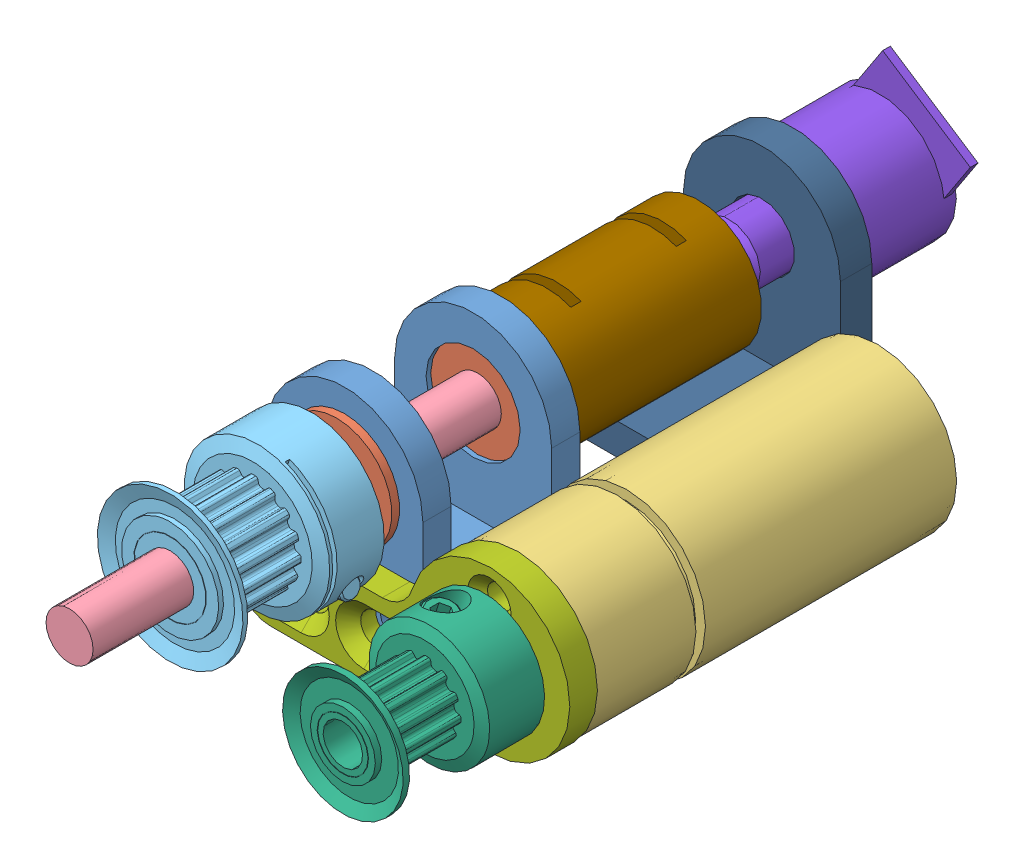
SolidWorks assembly head-pin-joint, configuration Default. Lengths in mm.
Overall size (34.59 24.97 83.16).
12 component instances, 11 part files, 25 mates.
Components (placement in the parent):
- n05-headyoke-1: n05-headyoke [Default] at origin size (15.88 21.91 15.88)
- p1875bearing-57155K319-MCM-1: p1875bearing-57155K319-MCM [Default] at (0 13.97 5.5499) x (0 0 -1) z (0 -1 0) size (3.17 11.18 11.18)
- p1875bearing-57155K319-MCM-2: p1875bearing-57155K319-MCM [Default] at (0 13.97 -5.5499) x (0 0 1) z (0 -1 0) size (3.17 11.18 11.18)
- MAXON-AMAX16-110049-110323-1: MAXON-AMAX16-110049-110323 [Default] at (17.4625 8.128 -28.5125) x (0 0 -1) z (1 0 0) size (48.2 16 16)
- n06-p1875shaft-1: n06-p1875shaft [Default] at (0 13.97 -15.0749) size (4.76 4.76 50.8)
- a_6d16-016df2506-p1875bore-16teeth-1: a_6d16-016df2506-p1875bore-16teeth [Default] at (0 13.97 17.218) x (0.167713 -0.985836 0) z (0 0 -1) size (14.73 14.73 14.29)
- a_6d16m012df6003-3mm-bored-to-4mm-1: a_6d16m012df6003-3mm-bored-to-4mm [Default] at (17.4625 8.128 17.2524) x (-0.948708 0.316155 0) z (0 0 -1) size (12.2 12.2 14.3)
- a_6n16-015df1206-2: a_6n16-015df1206 [Default] at (-14.2838 6.954 15.9813) x (0.986257 0.164531 -0.015045) z (-0.021924 0.040076 -0.998956) size (14.1 14.1 11.13) (hidden)
- n09-motor-holder-1: n09-motor-holder [Default] at (17.4625 8.128 7.9375) size (33.53 16.26 2.79)
- POT-eti-sys-EUP125-1: POT-eti-sys-EUP125 [Default] at (0 13.97 -47.4345) x (0 0 -1) z (0.836462 -0.548026 0) size (30.58 15.39 13)
- 000_helical-coupling-6208K53-MCM-1: 000_helical-coupling-6208K53-MCM [Default] at (0 13.97 -18.3769) size (12.7 12.7 19.05)
- n10-potholder-1: n10-potholder [Default] at (0 0 -29.5148) size (15.88 21.91 15.88)
Mates (geometry in assembly coordinates):
- Coincident1: coincident anti-aligned: plane of n05-headyoke-1 through (0 13.97 7.9375) normal (0 0 1); plane of p1875bearing-57155K319-MCM-1 through (4.7625 13.97 7.9375) normal (0 0 -1)
- Coincident2: coincident anti-aligned: plane of n05-headyoke-1 through (0 13.97 -7.9375) normal (0 0 -1); plane of p1875bearing-57155K319-MCM-2 through (-4.7625 13.97 -7.9375) normal (0 0 1)
- Concentric1: concentric anti-aligned: cylinder of n05-headyoke-1; cylinder of p1875bearing-57155K319-MCM-2
- Concentric2: concentric aligned: cylinder of n05-headyoke-1; cylinder of p1875bearing-57155K319-MCM-1
- Coincident3: coincident anti-aligned: plane of p1875bearing-57155K319-MCM-1 through (0 13.97 5.5499) normal (1 0 0); plane of p1875bearing-57155K319-MCM-2 through (0 13.97 -5.5499) normal (-1 0 0)
- Parallel1: parallel aligned: plane of n05-headyoke-1 through (7.9375 0 7.9375) normal (1 0 0); plane of p1875bearing-57155K319-MCM-1 through (0 13.97 5.5499) normal (1 0 0)
- Concentric3: concentric anti-aligned: cylinder of p1875bearing-57155K319-MCM-2; cylinder of n06-p1875shaft-1
- Distance1: distance = 6.35 mm aligned: plane of p1875bearing-57155K319-MCM-2 through (-5.588 13.97 -8.7249) normal (0 0 -1); plane of n06-p1875shaft-1 through (0 13.97 -15.0749) normal (0 0 -1)
- Concentric4: concentric aligned: cylinder of n06-p1875shaft-1; cylinder of a_6d16-016df2506-p1875bore-16teeth-1
- Distance2: distance = 2.54 mm anti-aligned: plane of p1875bearing-57155K319-MCM-1 through (5.588 13.97 8.7249) normal (0 0 1); plane of a_6d16-016df2506-p1875bore-16teeth-1 through (-7.2617 12.7346 11.2649) normal (0 0 -1)
- Coincident7: coincident aligned: plane of n05-headyoke-1 through (0 13.97 7.9375) normal (0 0 1); plane of MAXON-AMAX16-110049-110323-1 through (17.4625 16.128 7.9375) normal (0 0 1)
- Concentric5: concentric aligned: cylinder of MAXON-AMAX16-110049-110323-1; cylinder of a_6d16m012df6003-3mm-bored-to-4mm-1
- Coincident8: coincident aligned: plane of a_6d16-016df2506-p1875bore-16teeth-1 through (0 13.97 25.5524) normal (0 0 1); plane of a_6d16m012df6003-3mm-bored-to-4mm-1 through (17.4625 8.128 25.5524) normal (0 0 1)
- Concentric6: concentric aligned: cylinder of MAXON-AMAX16-110049-110323-1; cylinder of n09-motor-holder-1
- Coincident9: coincident anti-aligned: plane of MAXON-AMAX16-110049-110323-1 through (17.4625 16.128 7.9375) normal (0 0 1); plane of n09-motor-holder-1 through (17.4625 8.128 7.9375) normal (0 0 -1)
- Concentric7: concentric anti-aligned: cylinder of n05-headyoke-1; cylinder of n09-motor-holder-1
- Concentric8: concentric anti-aligned: cylinder of n05-headyoke-1; cylinder of n09-motor-holder-1
- Concentric9: concentric aligned: cylinder of MAXON-AMAX16-110049-110323-1; cylinder of n09-motor-holder-1
- Distance3: distance = 0.127 mm anti-aligned: plane of p1875bearing-57155K319-MCM-2; plane of 000_helical-coupling-6208K53-MCM-1 through (0 13.97 -8.8519) normal (0 0 1)
- Concentric10: concentric aligned: cylinder of n06-p1875shaft-1; cylinder of 000_helical-coupling-6208K53-MCM-1
- Distance4: distance = 2.54 mm anti-aligned: plane of POT-eti-sys-EUP125-1 through (1.74 16.6258 -30.4419) normal (0 0 1); plane of 000_helical-coupling-6208K53-MCM-1 through (0 13.97 -27.9019) normal (0 0 -1)
- Concentric11: concentric aligned: cylinder of POT-eti-sys-EUP125-1; cylinder of 000_helical-coupling-6208K53-MCM-1
- Coincident10: coincident anti-aligned: plane of POT-eti-sys-EUP125-1 through (3.5635 19.409 -37.4523) normal (0 0 1); plane of n10-potholder-1 through (0 13.97 -37.4523) normal (0 0 -1)
- Concentric12: concentric aligned: cylinder of POT-eti-sys-EUP125-1; cylinder of n10-potholder-1
- Coincident11: coincident aligned: plane of n05-headyoke-1 through (7.9375 0 7.9375) normal (0 -1 0); plane of n10-potholder-1 through (7.9375 0 -21.5773) normal (0 -1 0)
